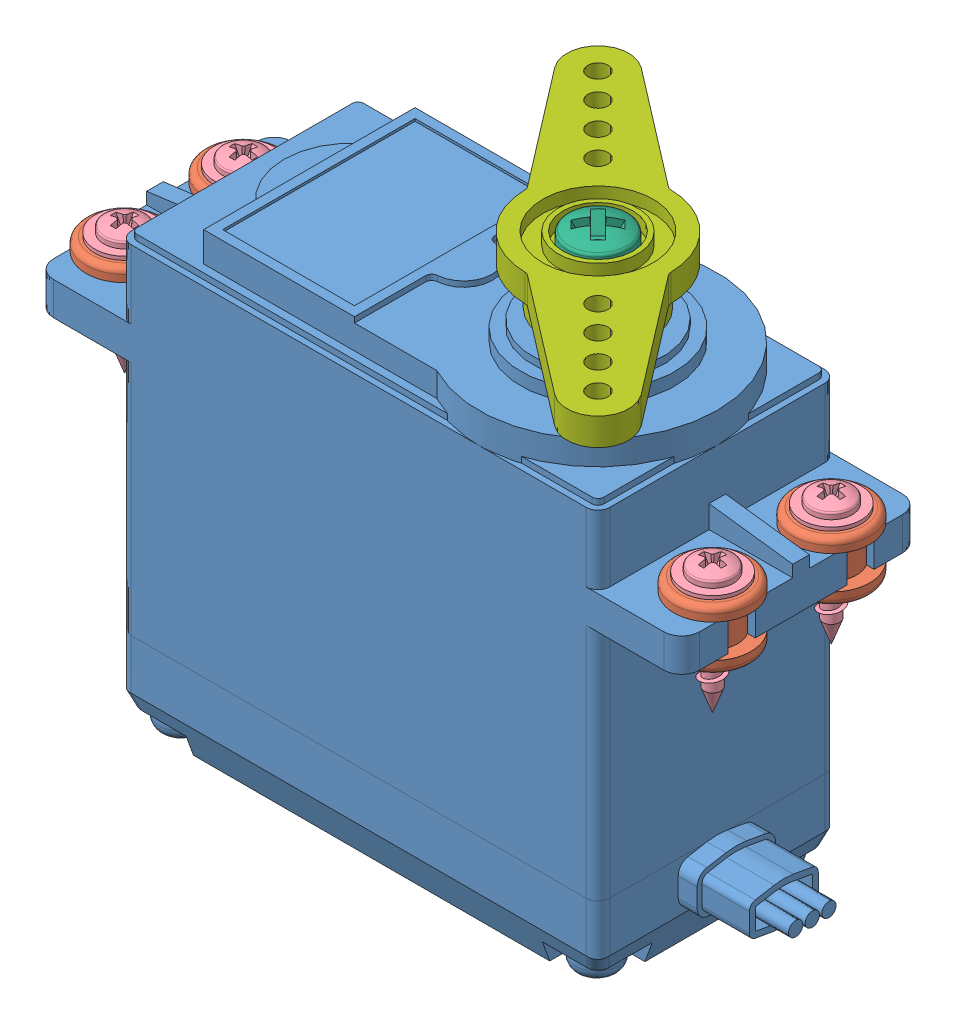
SolidWorks assembly FS5109M_Ensemble servo, configuration 2S. Lengths in mm.
Overall size (67.02 48.5 57.84).
26 component instances, 11 part files, 4 mates.
Components (placement in the parent):
- FS5109M_Ensemble corps-1: FS5109M_Ensemble corps [Défaut] at origin size (56.15 39.9 20.1)
  - FS5109M_corps-1: FS5109M_corps [Défaut] at origin size (55.35 39.9 20.1)
  - FS5109M_Ensemble silent-bloc-1: FS5109M_Ensemble silent-bloc [Défaut] at (-24.75 1.4 5) size (6.5 5.2 6.5)
    - FS5109M_silent-bloc-1: FS5109M_silent-bloc [Défaut] at origin size (6.5 5 6.5)
    - FS5109M_silent-bloc_douille-1: FS5109M_silent-bloc_douille [Défaut] at (0 -2.7 0) x (-1 0 0) z (0 0 1) size (4.5 5.2 4.5)
  - FS5109M_Ensemble silent-bloc-2: FS5109M_Ensemble silent-bloc [Défaut] at (-24.75 1.4 -5) size (6.5 5.2 6.5)
    - FS5109M_silent-bloc-1: FS5109M_silent-bloc [Défaut] at origin size (6.5 5 6.5)
    - FS5109M_silent-bloc_douille-1: FS5109M_silent-bloc_douille [Défaut] at (0 -2.7 0) x (-1 0 0) z (0 0 1) size (4.5 5.2 4.5)
  - FS5109M_Ensemble silent-bloc-3: FS5109M_Ensemble silent-bloc [Défaut] at (24.75 1.4 -5) x (-1 0 0) z (0 0 -1) size (6.5 5.2 6.5)
    - FS5109M_silent-bloc-1: FS5109M_silent-bloc [Défaut] at origin size (6.5 5 6.5)
    - FS5109M_silent-bloc_douille-1: FS5109M_silent-bloc_douille [Défaut] at (0 -2.7 0) x (-1 0 0) z (0 0 1) size (4.5 5.2 4.5)
  - FS5109M_Ensemble silent-bloc-4: FS5109M_Ensemble silent-bloc [Défaut] at (24.75 1.4 5) x (-1 0 0) z (0 0 -1) size (6.5 5.2 6.5)
    - FS5109M_silent-bloc-1: FS5109M_silent-bloc [Défaut] at origin size (6.5 5 6.5)
    - FS5109M_silent-bloc_douille-1: FS5109M_silent-bloc_douille [Défaut] at (0 -2.7 0) x (-1 0 0) z (0 0 1) size (4.5 5.2 4.5)
  - FS5109M_vis servo 2 x 10-1: FS5109M_vis servo 2 x 10 [ISO 7045 - M2 x 10 - Z --- 10N] at (-24.75 5.2 5) x (0 -1 0) z (0 0 -1) size (11.27 5 5)
  - FS5109M_vis servo 2 x 10-2: FS5109M_vis servo 2 x 10 [ISO 7045 - M2 x 10 - Z --- 10N] at (-24.75 5.2 -5) x (0 -1 0) z (0 0 -1) size (11.27 5 5)
  - FS5109M_vis servo 2 x 10-3: FS5109M_vis servo 2 x 10 [ISO 7045 - M2 x 10 - Z --- 10N] at (24.75 5.2 -5) x (0 -1 0) z (0 0 1) size (11.27 5 5)
  - FS5109M_vis servo 2 x 10-4: FS5109M_vis servo 2 x 10 [ISO 7045 - M2 x 10 - Z --- 10N] at (24.75 5.2 5) x (0 -1 0) z (0 0 1) size (11.27 5 5)
- FS5109M_Ensemble arbre-1: FS5109M_Ensemble arbre [2S] at (10.1 -27.1 0) x (0.707107 0 0.707107) z (-0.707107 0 0.707107) size (55.74 14.3 36.6)
  - FS5109M_arbre-1: FS5109M_arbre [Défaut] at origin size (6 10 6)
  - FS5109M_vis arbre M3 x 6-1: FS5109M_vis arbre M3 x 6 [vis arbre M3 x 6] at (0 47.05 0) x (0 -1 0) z (0 0 1) size (7.75 5.1 5.1)
  - FS5109M_palo 2S-1: FS5109M_palo 2S [Défaut] at (0 44.2 0) size (38.2 5.6 12.15)
  - FS5109M_palo 2B-1: FS5109M_palo 2B [Défaut] at (0 44.2 0) size (55.74 7.8 13.34) (hidden)
  - FS5109M_palo C-1: FS5109M_palo C [Défaut] at (0 44.2 0) size (20.9 5.6 20.9) (hidden)
  - FS5109M_palo 4-1: FS5109M_palo 4 [Défaut] at (0 44.2 0) size (36.6 5.6 36.6) (hidden)
  - FS5109M_palo 6-1: FS5109M_palo 6 [Défaut] at (0 44.2 0) size (31.74 5.6 28.12) (hidden)
Mates (geometry in assembly coordinates):
- Coïncidente1: coordinate: point of FS5109M_Ensemble corps-1/FS5109M_corps-1
- Coïncidente2: coincident aligned: line of FS5109M_Ensemble corps-1/FS5109M_corps-1 through (10.1 0 0) axis (0 1 0); line of FS5109M_Ensemble arbre-1/FS5109M_arbre-1 through (10.1 -27.1 0) axis (0 1 0)
- Coïncidente3: coincident anti-aligned: plane of FS5109M_Ensemble corps-1/FS5109M_corps-1 through (-20.15 -27.1 10.05) normal (0 -1 0); plane of FS5109M_Ensemble arbre-1/FS5109M_arbre-1
- Angle1: planar angle = 0.785398 rad aligned: plane of FS5109M_Ensemble arbre-1/FS5109M_arbre-1 through (10.1 -27.1 0) normal (-0.707107 0 0.707107); plane of FS5109M_Ensemble corps-1/FS5109M_corps-1 through (0 0 0) normal (0 0 1)
